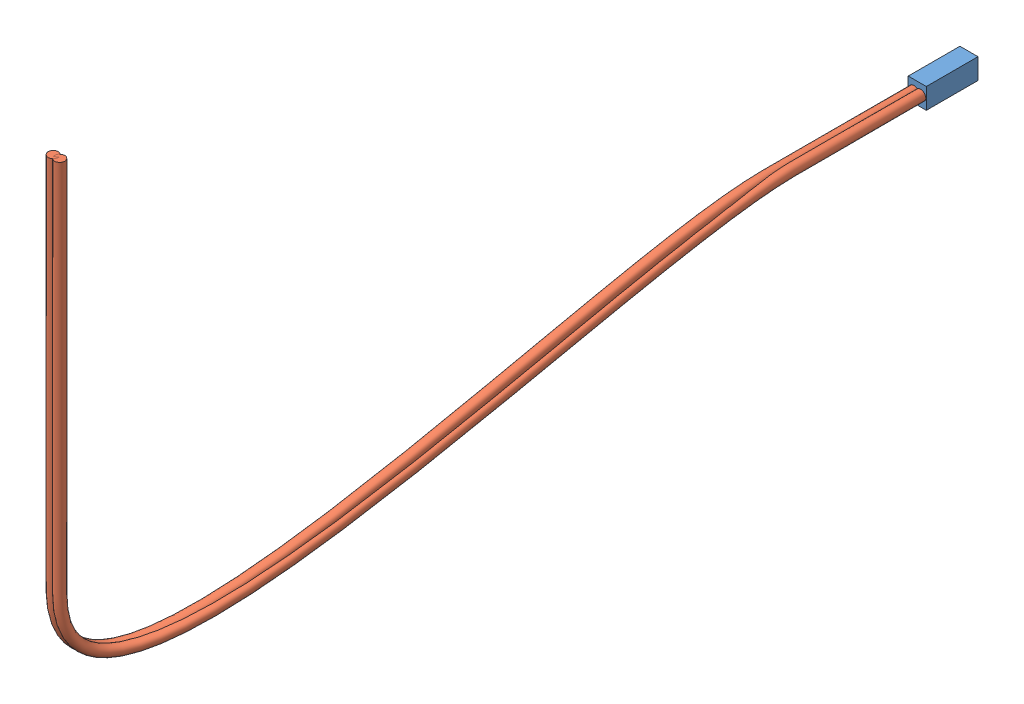
SolidWorks assembly Harness_4-CABLE_HARNESSING_ASSEMBLY, configuration Default. Lengths in mm.
Overall size (35.8 87.22 147.65).
3 component instances, 3 part files, 0 mates.
Components (placement in the parent):
- 02_PIN-1: 02_PIN [Default] at (5.9755 -0.2863 -123.4553) size (3.5 4 20)
- Cable^Harness_4-CABLE_HARNESSING_ASSEMBLY-1: Cable^Harness_4-CABLE_HARNESSING_ASSEMBLY [Default] at origin size (35.8 87.22 138.4) (virtual)
- Flattened_Cable^Harness_4-CABLE_HARNESSING_ASSEMBLY-1: Flattened_Cable^Harness_4-CABLE_HARNESSING_ASSEMBLY [Default] at origin (suppressed, hidden, virtual)
